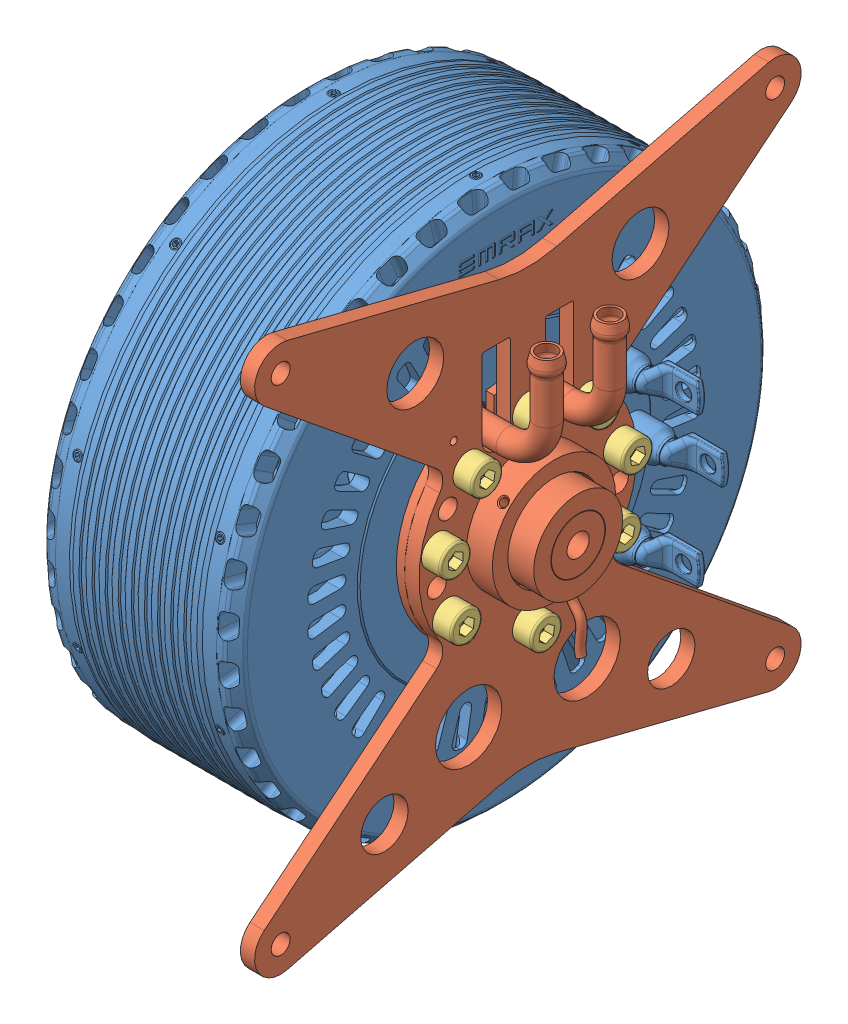
SolidWorks assembly 228_lc_resolver, configuration Default. Lengths in mm.
Overall size (122.67 230.6 230.6).
11 component instances, 3 part files, 0 mates.
Components (placement in the parent):
- 228_lc_resolver.step-1: 228_lc_resolver.step [Default] at origin size (122.67 230.6 230.6)
  - 228_A01.step-1: 228_A01.step [Default] at origin size (121 228 228)
  - 228_dodatki.step-1: 228_dodatki.step [Default] at origin size (70.09 230.6 230.6)
  - socket head cap screw_din_DIN 912 M8 x 20 --- 20N.step-1: socket head cap screw_din_DIN 912 M8 x 20 --- 20N.step [Default] at (85.5 -19.5 -33.775) x (-1 0 0) z (0 -0.959673 -0.281117) size (28 13 13)
  - socket head cap screw_din_DIN 912 M8 x 20 --- 20N.step-2: socket head cap screw_din_DIN 912 M8 x 20 --- 20N.step [Default] at (85.5 29.8757 25.0687) x (-1 0 0) z (0 0.924225 0.381849) size (28 13 13)
  - socket head cap screw_din_DIN 912 M8 x 20 --- 20N.step-3: socket head cap screw_din_DIN 912 M8 x 20 --- 20N.step [Default] at (85.5 39 0) x (-1 0 0) z (0 0.924225 0.381849) size (28 13 13)
  - socket head cap screw_din_DIN 912 M8 x 20 --- 20N.step-4: socket head cap screw_din_DIN 912 M8 x 20 --- 20N.step [Default] at (85.5 -39 0) x (-1 0 0) z (0 0.924225 0.381849) size (28 13 13)
  - socket head cap screw_din_DIN 912 M8 x 20 --- 20N.step-5: socket head cap screw_din_DIN 912 M8 x 20 --- 20N.step [Default] at (85.5 -19.5 33.775) x (-1 0 0) z (0 0.924225 0.381849) size (28 13 13)
  - socket head cap screw_din_DIN 912 M8 x 20 --- 20N.step-6: socket head cap screw_din_DIN 912 M8 x 20 --- 20N.step [Default] at (85.5 29.8757 -25.0687) x (-1 0 0) z (0 -0.659015 -0.752129) size (28 13 13)
  - socket head cap screw_din_DIN 912 M8 x 20 --- 20N.step-7: socket head cap screw_din_DIN 912 M8 x 20 --- 20N.step [Default] at (85.5 6.7723 38.4075) x (-1 0 0) z (0 0.85199 0.523557) size (28 13 13)
  - socket head cap screw_din_DIN 912 M8 x 20 --- 20N.step-8: socket head cap screw_din_DIN 912 M8 x 20 --- 20N.step [Default] at (85.5 6.7723 -38.4075) x (-1 0 0) z (0 0.77839 0.627782) size (28 13 13)
